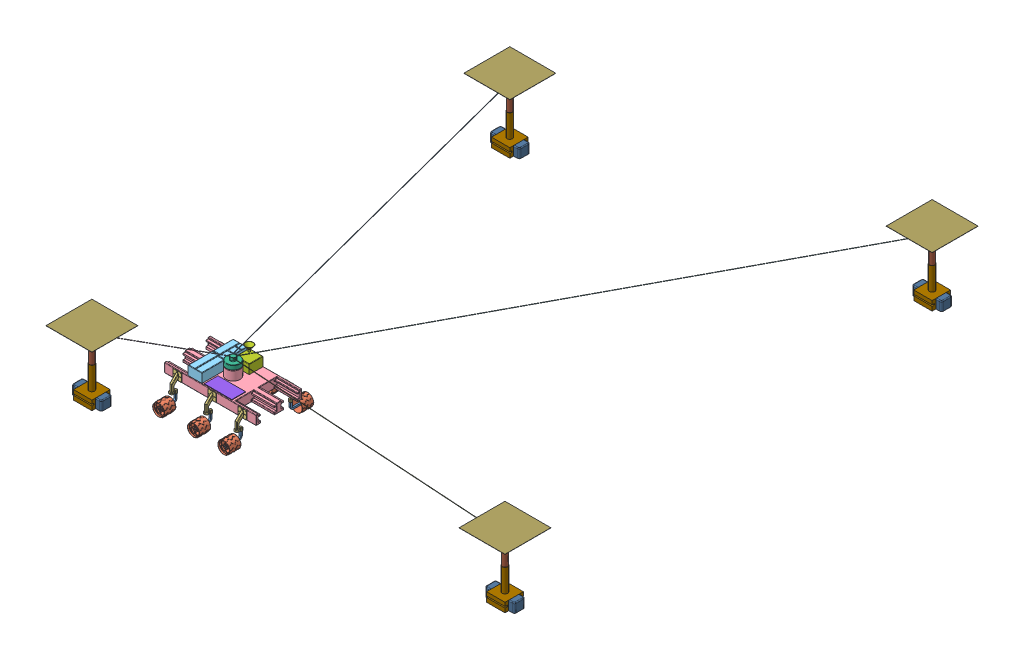
SolidWorks assembly expanced, configuration Default. Lengths in mm.
Overall size (12696.43 3283.04 12717.4).
76 component instances, 18 part files, 41 mates.
Components (placement in the parent):
- lg-1: lg [Default] at (784.667 1146.0693 1417.0512) size (2000 1056.21 1833.55)
  - act2-1: act2 [Default] at (710 -374.097 990.1927) x (0 1 0) z (1 0 0) size (227.86 360.36 100)
  - Wheel-1: Wheel [Default] at (710 -349.0008 1023.6376) x (0 1 0) z (0 0 -1) size (274.42 270 250)
  - act1-1: act1 [Default] at (710 -171.1455 626.4214) x (-1 0 0) z (0 0 -1) size (180 401.15 176.42)
  - body-1: body [Default] at origin size (2000 400 1000)
  - act1-2: act1 [Default] at (-710 -171.1455 626.4214) x (-1 0 0) z (0 0 -1) size (180 401.15 176.42)
  - Wheel-2: Wheel [Default] at (-710 -349.0008 1023.6376) x (-1 0 0) z (0 0 -1) size (274.42 270 250)
  - act2-2: act2 [Default] at (-710 -374.097 990.1927) x (0 1 0) z (1 0 0) size (227.86 360.36 100)
  - Wheel-3: Wheel [Default] at (-710 -349.0008 -1023.6376) size (274.42 270 250)
  - act2-3: act2 [Default] at (-710 -374.097 -990.1927) x (0 1 0) z (-1 0 0) size (227.86 360.36 100)
  - act1-3: act1 [Default] at (-710 -171.1455 -626.4214) size (180 401.15 176.42)
  - act1-4: act1 [Default] at (710 -171.1455 -626.4214) size (180 401.15 176.42)
  - Wheel-4: Wheel [Default] at (710 -349.0008 -1023.6376) x (0 -1 0) z (0 0 1) size (274.42 270 250)
  - act2-4: act2 [Default] at (710 -374.097 -990.1927) x (0 1 0) z (-1 0 0) size (227.86 360.36 100)
  - tool box-1: tool box [Default] at (-340 200 0) x (0 0 1) z (-1 0 0) size (980 200 300)
  - act1-5: act1 [Default] at (50 -171.1455 626.4214) x (-1 0 0) z (0 0 -1) size (180 401.15 176.42)
  - act2-5: act2 [Default] at (50 -374.097 990.1927) x (0 1 0) z (1 0 0) size (227.86 360.36 100)
  - Wheel-5: Wheel [Default] at (50 -349.0008 1023.6376) x (-1 0 0) z (0 0 -1) size (274.42 270 250)
  - arm-1: arm [Default] at (0 400 0) x (0.719935 0 0.694042) z (-0.694042 0 0.719935) size (300 300 300)
  - Lab-1: Lab [Default] at (10 200 -340) x (0 0 1) z (-1 0 0) size (324.09 330 324.09)
  - Wheel-6: Wheel [Default] at (50 -349.0008 -1023.6376) size (274.42 270 250)
  - act1-6: act1 [Default] at (50 -171.1455 -626.4214) size (180 401.15 176.42)
  - act2-6: act2 [Default] at (50 -374.097 -990.1927) x (0 1 0) z (-1 0 0) size (227.86 360.36 100)
  - solar panel-1: solar panel [Default] at (150 200 330) size (600 10 300)
- pole-5: pole [Default] at (-3047.9379 27.5984 3488.5519) x (0 0 -1) z (1 0 0) size (1000 1406.95 1000)
  - pilon-1: pilon [Default] at (750.6878 634.4701 2074.8363) size (400 700 400)
  - fix-1: fix [Default] at (704.1878 324.4701 2336.3363) size (236 530 123)
    - screw - Copy-1: screw - Copy [Default] at origin size (83 330 83) (hidden)
    - Part3^fix-1: Part3^fix [Default] at origin size (236 200 123) (virtual)
    - screw2 - Copy - Copy-1: screw2 - Copy - Copy [Default] at (97.0846 0 0) size (83 330 83) (hidden)
  - fix-2: fix [Default] at (797.1878 324.4701 1813.3363) x (-1 0 0) z (0 0 -1) size (236 530 123)
    - screw - Copy-1: screw - Copy [Default] at origin size (83 330 83) (hidden)
    - Part3^fix-1: Part3^fix [Default] at origin size (236 200 123) (virtual)
    - screw2 - Copy - Copy-1: screw2 - Copy - Copy [Default] at (97.0846 0 0) size (83 330 83) (hidden)
  - pilon2-1: pilon2 [Default] at (750.6878 1327.4202 2074.8363) x (-0.067113 0 0.997745) z (-0.997745 0 -0.067113) size (110 500 110)
  - cap-2: cap [Default] at (750.6878 1827.4202 2074.8363) x (0 0 1) z (-1 0 0) size (1000 264 1000)
- pole-6: pole [Default] at (-3041.7663 244.2856 -5613.3459) x (0 0 -1) z (1 0 0) size (1000 1406.95 1000)
  - pilon-1: pilon [Default] at (750.6878 634.4701 2074.8363) size (400 700 400)
  - fix-1: fix [Default] at (704.1878 324.4701 2336.3363) size (236 530 123)
    - screw - Copy-1: screw - Copy [Default] at origin size (83 330 83) (hidden)
    - Part3^fix-1: Part3^fix [Default] at origin size (236 200 123) (virtual)
    - screw2 - Copy - Copy-1: screw2 - Copy - Copy [Default] at (97.0846 0 0) size (83 330 83) (hidden)
  - fix-2: fix [Default] at (797.1878 324.4701 1813.3363) x (-1 0 0) z (0 0 -1) size (236 530 123)
    - screw - Copy-1: screw - Copy [Default] at origin size (83 330 83) (hidden)
    - Part3^fix-1: Part3^fix [Default] at origin size (236 200 123) (virtual)
    - screw2 - Copy - Copy-1: screw2 - Copy - Copy [Default] at (97.0846 0 0) size (83 330 83) (hidden)
  - pilon2-1: pilon2 [Default] at (750.6878 1327.4202 2074.8363) x (-0.067113 0 0.997745) z (-0.997745 0 -0.067113) size (110 500 110)
  - cap-2: cap [Default] at (750.6878 1827.4202 2074.8363) x (0 0 1) z (-1 0 0) size (1000 264 1000)
- pole-7: pole [Default] at (6101.7709 1901.4786 -5672.0737) x (0 0 -1) z (1 0 0) size (1000 1406.95 1000)
  - pilon-1: pilon [Default] at (750.6878 634.4701 2074.8363) size (400 700 400)
  - fix-1: fix [Default] at (704.1878 324.4701 2336.3363) size (236 530 123)
    - screw - Copy-1: screw - Copy [Default] at origin size (83 330 83) (hidden)
    - Part3^fix-1: Part3^fix [Default] at origin size (236 200 123) (virtual)
    - screw2 - Copy - Copy-1: screw2 - Copy - Copy [Default] at (97.0846 0 0) size (83 330 83) (hidden)
  - fix-2: fix [Default] at (797.1878 324.4701 1813.3363) x (-1 0 0) z (0 0 -1) size (236 530 123)
    - screw - Copy-1: screw - Copy [Default] at origin size (83 330 83) (hidden)
    - Part3^fix-1: Part3^fix [Default] at origin size (236 200 123) (virtual)
    - screw2 - Copy - Copy-1: screw2 - Copy - Copy [Default] at (97.0846 0 0) size (83 330 83) (hidden)
  - pilon2-1: pilon2 [Default] at (750.6878 1327.4202 2074.8363) x (-0.067113 0 0.997745) z (-0.997745 0 -0.067113) size (110 500 110)
  - cap-2: cap [Default] at (750.6878 1827.4202 2074.8363) x (0 0 1) z (-1 0 0) size (1000 264 1000)
- pole-8: pole [Default] at (6069.3138 829.251 3603.6778) x (0 0 -1) z (1 0 0) size (1000 1406.95 1000)
  - pilon-1: pilon [Default] at (750.6878 634.4701 2074.8363) size (400 700 400)
  - fix-1: fix [Default] at (704.1878 324.4701 2336.3363) size (236 530 123)
    - screw - Copy-1: screw - Copy [Default] at origin size (83 330 83) (hidden)
    - Part3^fix-1: Part3^fix [Default] at origin size (236 200 123) (virtual)
    - screw2 - Copy - Copy-1: screw2 - Copy - Copy [Default] at (97.0846 0 0) size (83 330 83) (hidden)
  - fix-2: fix [Default] at (797.1878 324.4701 1813.3363) x (-1 0 0) z (0 0 -1) size (236 530 123)
    - screw - Copy-1: screw - Copy [Default] at origin size (83 330 83) (hidden)
    - Part3^fix-1: Part3^fix [Default] at origin size (236 200 123) (virtual)
    - screw2 - Copy - Copy-1: screw2 - Copy - Copy [Default] at (97.0846 0 0) size (83 330 83) (hidden)
  - pilon2-1: pilon2 [Default] at (750.6878 1327.4202 2074.8363) x (-0.067113 0 0.997745) z (-0.997745 0 -0.067113) size (110 500 110)
  - cap-2: cap [Default] at (750.6878 1827.4202 2074.8363) x (0 0 1) z (-1 0 0) size (1000 264 1000)
- Part1^expanced-1: Part1^expanced [Default] at (784.667 1716.0693 1417.0512) x (0.719935 0 0.694042) z (0 1 0) size (1104.05 2118.53 193.95) (virtual)
- Part2^expanced-1: Part2^expanced [Default] at (784.667 1716.0693 1417.0512) x (0.719935 0 0.694042) z (0 1 0) size (6613.68 4398.52 410.64) (virtual)
- Part3^expanced-2: Part3^expanced [Default] at (784.667 1716.0693 1417.0512) x (0.719935 0 0.694042) z (0 1 0) size (131.69 10726.8 2067.83) (virtual)
- Part4^expanced-2: Part4^expanced [Default] at (784.667 1716.0693 1417.0512) x (0.719935 0 0.694042) z (0 1 0) size (6247.2 4081.67 995.6) (virtual)
Mates (geometry in assembly coordinates):
- Coincident1: coincident: plane of lg-1/body-1 through (1784.667 1146.0693 1867.0512) normal (0 0 -1); plane of ? through (1807.667 1396.0693 1867.0512) normal (0 0 1)
- Coincident2: coincident: plane of lg-1/body-1 through (1284.667 1346.0693 1917.0512) normal (1 0 0); plane of ? through (1284.667 1396.0693 1589.0512) normal (-1 0 0)
- Coincident3: coincident: plane of lg-1/body-1 through (1784.667 1196.0693 1417.0512) normal (0 1 0); plane of ? through (1607.667 1196.0693 1667.0512) normal (0 -1 0)
- Coincident4: coincident: plane of lg-1/body-1 through (1784.667 1146.0693 967.0512) normal (0 0 1); plane of ? through (1807.667 1396.0693 967.0512) normal (0 0 -1)
- Coincident5: coincident: plane of lg-1/body-1 through (1284.667 1346.0693 1917.0512) normal (1 0 0); plane of ? through (1284.667 1396.0693 1089.0512) normal (-1 0 0)
- Coincident6: coincident: plane of lg-1/body-1 through (1784.667 1196.0693 1417.0512) normal (0 1 0); plane of ? through (1607.667 1196.0693 1167.0512) normal (0 -1 0)
- Coincident7: coincident: plane of lg-1/body-1 through (-215.333 1146.0693 967.0512) normal (0 0 1); plane of ? through (161.667 1396.0693 967.0512) normal (0 0 -1)
- Coincident8: coincident: plane of lg-1/body-1 through (284.667 1346.0693 1917.0512) normal (-1 0 0); plane of ? through (284.667 1396.0693 1245.0512) normal (1 0 0)
- Coincident9: coincident: plane of lg-1/body-1 through (-215.333 1196.0693 1417.0512) normal (0 1 0); plane of ? through (-38.333 1196.0693 1167.0512) normal (0 -1 0)
- Coincident10: coincident: plane of lg-1/body-1 through (-215.333 1146.0693 1867.0512) normal (0 0 -1); plane of ? through (161.667 1396.0693 1867.0512) normal (0 0 1)
- Coincident11: coincident: plane of lg-1/body-1 through (284.667 1346.0693 1917.0512) normal (-1 0 0); plane of ? through (284.667 1396.0693 1745.0512) normal (1 0 0)
- Coincident12: coincident: plane of lg-1/body-1 through (-215.333 1196.0693 1417.0512) normal (0 1 0); plane of ? through (-38.333 1196.0693 1667.0512) normal (0 -1 0)
- InPlace1: in place: plane of lg-1/arm-1 through (784.667 1716.0693 1417.0512) normal (0 1 0); plane of ? through (0 1716.0693 0) normal (0 1 0); moOrthogonalPlaneRef_w of lg-1/arm-1 through (784.667 1716.0693 1417.0512) normal (0 1 0); plane of ? through (0 1716.0693 0) normal (0 0 -1); plane of lg-1/arm-1 through (784.667 1716.0693 1417.0512) normal (0 1 0); plane of ? through (0 1716.0693 0) normal (1 0 0); plane of lg-1/arm-1 through (784.667 1716.0693 1417.0512) normal (0 1 0); unknown of ?
- Coincident13: coincident: plane of lg-1/arm-1 through (784.667 1716.0693 1417.0512) normal (0 1 0); plane of Part1^expanced-1 through (784.667 1716.0693 1417.0512) normal (0 1 0)
- Coincident14: coincident: moOrthogonalPlaneRef_w of lg-1/arm-1 through (784.667 1716.0693 1417.0512) normal (0.694042 0 -0.719935); plane of Part1^expanced-1 through (784.667 1716.0693 1417.0512) normal (0.694042 0 -0.719935)
- Coincident15: coincident: moOrthogonalPlaneRef_w of lg-1/arm-1 through (784.667 1716.0693 1417.0512) normal (-0.719935 0 -0.694042); plane of Part1^expanced-1 through (784.667 1716.0693 1417.0512) normal (0.719935 0 0.694042)
- InPlace2: in place: plane of lg-1/arm-1 through (784.667 1716.0693 1417.0512) normal (0 1 0); plane of ? through (0 1716.0693 0) normal (0 1 0); plane of lg-1/arm-1 through (784.667 1716.0693 1417.0512) normal (0 1 0); plane of ? through (0 1716.0693 0) normal (0 0 -1); plane of lg-1/arm-1 through (784.667 1716.0693 1417.0512) normal (0 1 0); plane of ? through (0 1716.0693 0) normal (1 0 0); plane of lg-1/arm-1 through (784.667 1716.0693 1417.0512) normal (0 1 0); unknown of ?
- Coincident16: coincident: plane of lg-1/arm-1; plane of Part2^expanced-1
- Coincident17: coincident: moOrthogonalPlaneRef_w of lg-1/arm-1 through (784.667 1716.0693 1417.0512) normal (0.694042 0 -0.719935); plane of Part2^expanced-1 through (784.667 1716.0693 1417.0512) normal (0.694042 0 -0.719935)
- Coincident18: coincident: moOrthogonalPlaneRef_w of lg-1/arm-1 through (784.667 1716.0693 1417.0512) normal (-0.719935 0 -0.694042); plane of Part2^expanced-1 through (784.667 1716.0693 1417.0512) normal (0.719935 0 0.694042)
- Distance1: distance = 0 mm: plane of pole-5/pilon-1 through (-973.1016 662.0685 2737.8642) normal (0 -1 0); plane of lg-1/Wheel-2 through (74.667 662.0685 2333.8279) normal (0 -1 0)
- InPlace3: in place: plane of lg-1/arm-1 through (784.667 1716.0693 1417.0512) normal (0 1 0); plane of ? through (0 1716.0693 0) normal (0 1 0); plane of lg-1/arm-1 through (784.667 1716.0693 1417.0512) normal (0 1 0); plane of ? through (0 1716.0693 0) normal (0 0 -1); plane of lg-1/arm-1 through (784.667 1716.0693 1417.0512) normal (0 1 0); plane of ? through (0 1716.0693 0) normal (1 0 0); plane of lg-1/arm-1 through (784.667 1716.0693 1417.0512) normal (0 1 0); unknown of ?
- Coincident19: coincident: plane of lg-1/arm-1; plane of ?
- Coincident20: coincident: moOrthogonalPlaneRef_w of lg-1/arm-1 through (784.667 1716.0693 1417.0512) normal (0.694042 0 -0.719935); plane of ? through (784.667 1716.0693 1417.0512) normal (0.694042 0 -0.719935)
- Coincident21: coincident: moOrthogonalPlaneRef_w of lg-1/arm-1 through (784.667 1716.0693 1417.0512) normal (-0.719935 0 -0.694042); plane of ? through (784.667 1716.0693 1417.0512) normal (0.719935 0 0.694042)
- InPlace4: in place: plane of lg-1/arm-1 through (784.667 1716.0693 1417.0512) normal (0 1 0); plane of ? through (0 1716.0693 0) normal (0 1 0); plane of lg-1/arm-1 through (784.667 1716.0693 1417.0512) normal (0 1 0); plane of ? through (0 1716.0693 0) normal (0 0 -1); plane of lg-1/arm-1 through (784.667 1716.0693 1417.0512) normal (0 1 0); plane of ? through (0 1716.0693 0) normal (1 0 0); plane of lg-1/arm-1 through (784.667 1716.0693 1417.0512) normal (0 1 0); unknown of ?
- Coincident22: coincident: plane of lg-1/arm-1; plane of ?
- Coincident23: coincident: moOrthogonalPlaneRef_w of lg-1/arm-1 through (784.667 1716.0693 1417.0512) normal (0.694042 0 -0.719935); plane of ? through (784.667 1716.0693 1417.0512) normal (0.694042 0 -0.719935)
- Coincident24: coincident: moOrthogonalPlaneRef_w of lg-1/arm-1 through (784.667 1716.0693 1417.0512) normal (-0.719935 0 -0.694042); plane of ? through (784.667 1716.0693 1417.0512) normal (0.719935 0 0.694042)
- InPlace5: in place: plane of lg-1/arm-1 through (784.667 1716.0693 1417.0512) normal (0 1 0); plane of ? through (0 1716.0693 0) normal (0 1 0); plane of lg-1/arm-1 through (784.667 1716.0693 1417.0512) normal (0 1 0); plane of ? through (0 1716.0693 0) normal (0 0 -1); plane of lg-1/arm-1 through (784.667 1716.0693 1417.0512) normal (0 1 0); plane of ? through (0 1716.0693 0) normal (1 0 0); plane of lg-1/arm-1 through (784.667 1716.0693 1417.0512) normal (0 1 0); unknown of ?
- Coincident13: coincident: plane of lg-1/arm-1; plane of Part2^expanced-1
- Coincident14: coincident: moOrthogonalPlaneRef_w of lg-1/arm-1 through (784.667 1716.0693 1417.0512) normal (0.694042 0 -0.719935); plane of Part2^expanced-1 through (784.667 1716.0693 1417.0512) normal (0.694042 0 -0.719935)
- Coincident15: coincident: moOrthogonalPlaneRef_w of lg-1/arm-1 through (784.667 1716.0693 1417.0512) normal (-0.719935 0 -0.694042); plane of Part2^expanced-1 through (784.667 1716.0693 1417.0512) normal (0.719935 0 0.694042)
- InPlace6: in place: plane of lg-1/arm-1 through (784.667 1716.0693 1417.0512) normal (0 1 0); plane of ? through (0 1716.0693 0) normal (0 1 0); plane of lg-1/arm-1 through (784.667 1716.0693 1417.0512) normal (0 1 0); plane of ? through (0 1716.0693 0) normal (0 0 -1); plane of lg-1/arm-1 through (784.667 1716.0693 1417.0512) normal (0 1 0); plane of ? through (0 1716.0693 0) normal (1 0 0); plane of lg-1/arm-1 through (784.667 1716.0693 1417.0512) normal (0 1 0); unknown of ?
- Coincident16: coincident: plane of lg-1/arm-1; plane of Part3^expanced-2
- Coincident17: coincident: moOrthogonalPlaneRef_w of lg-1/arm-1 through (784.667 1716.0693 1417.0512) normal (0.694042 0 -0.719935); plane of Part3^expanced-2 through (784.667 1716.0693 1417.0512) normal (0.694042 0 -0.719935)
- Coincident18: coincident: moOrthogonalPlaneRef_w of lg-1/arm-1 through (784.667 1716.0693 1417.0512) normal (-0.719935 0 -0.694042); plane of Part3^expanced-2 through (784.667 1716.0693 1417.0512) normal (0.719935 0 0.694042)
- InPlace7: in place: plane of lg-1/arm-1 through (784.667 1716.0693 1417.0512) normal (0 1 0); plane of ? through (0 1716.0693 0) normal (0 1 0); plane of lg-1/arm-1 through (784.667 1716.0693 1417.0512) normal (0 1 0); plane of ? through (0 1716.0693 0) normal (0 0 -1); plane of lg-1/arm-1 through (784.667 1716.0693 1417.0512) normal (0 1 0); plane of ? through (0 1716.0693 0) normal (1 0 0); plane of lg-1/arm-1 through (784.667 1716.0693 1417.0512) normal (0 1 0); unknown of ?
- Coincident19: coincident: plane of lg-1/arm-1; plane of Part4^expanced-2
- Coincident20: coincident: moOrthogonalPlaneRef_w of lg-1/arm-1 through (784.667 1716.0693 1417.0512) normal (0.694042 0 -0.719935); plane of Part4^expanced-2 through (784.667 1716.0693 1417.0512) normal (0.694042 0 -0.719935)
- Coincident21: coincident: moOrthogonalPlaneRef_w of lg-1/arm-1 through (784.667 1716.0693 1417.0512) normal (-0.719935 0 -0.694042); plane of Part4^expanced-2 through (784.667 1716.0693 1417.0512) normal (0.719935 0 0.694042)
